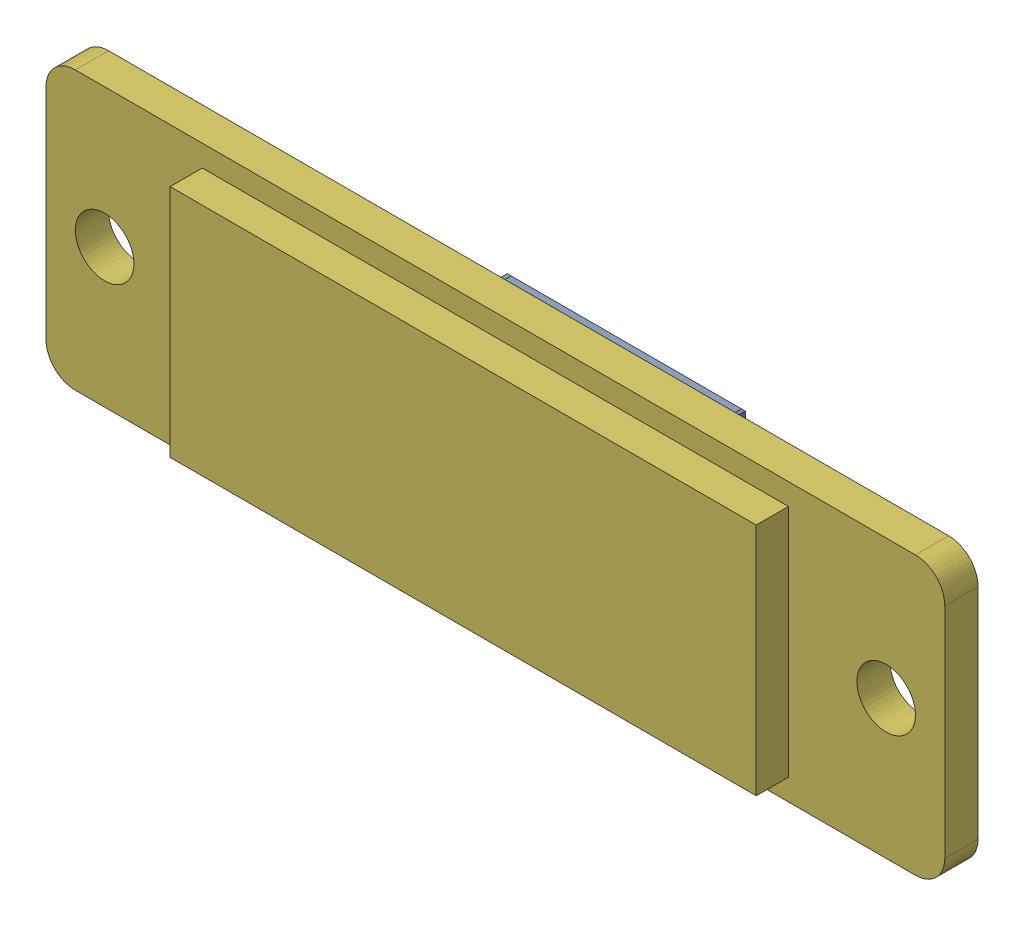
SolidWorks assembly OLED-JT, configuration Default. Lengths in mm.
Overall size (46 14.2 8.35).
36 component instances, 8 part files, 0 mates.
Components (placement in the parent):
- 4PIN-1: 4PIN [Default] at (6.97 53 -1.7) x (0 -1 0) z (0 0 -1) size (8.63 12.19 5)
  - 739168144-1: 739168144 [Default] at (53.0673 7.4627 4.5) size (6.13 11.96 0.5)
    - Extruded (28)_1-1: Extruded (28)_1 [Default] at origin size (6.13 11.96 0.5)
  - 739168272-1: 739168272 [Default] at (56.0287 7.45 0) size (0.2 12 4.5)
    - Extruded (29)_1-1: Extruded (29)_1 [Default] at origin size (0.2 12 4.5)
  - 739168528-1: 739168528 [Default] at (53.738 13.4444 0) size (7.47 0.2 5)
    - Extruded (30)_1-1: Extruded (30)_1 [Default] at origin size (7.47 0.2 5)
  - 739168656-1: 739168656 [Default] at (53.066 7.4627 0) size (6.12 11.96 0.5)
    - Extruded (31)_1-1: Extruded (31)_1 [Default] at origin size (6.12 11.96 0.5)
  - 739168528_1-1: 739168528_1 [Default] at (53.738 1.4556 0) size (7.47 0.2 5)
    - Extruded (30)_1-1: Extruded (30)_1 [Default] at origin size (7.47 0.2 5)
  - 654176208-1: 654176208 [Default] at (56.1305 4.4303 2.5) x (0 0 -1) z (-1 0 0) size (0.8 0.8 5)
    - Cylinder (1)_1-1: Cylinder (1)_1 [Default] at origin size (0.8 0.8 5)
  - 654176208_1-1: 654176208_1 [Default] at (56.1305 6.4661 2.5) x (0 0 -1) z (-1 0 0) size (0.8 0.8 5)
    - Cylinder (1)_1-1: Cylinder (1)_1 [Default] at origin size (0.8 0.8 5)
  - 654176208_2-1: 654176208_2 [Default] at (56.1305 8.4727 2.5) x (0 0 -1) z (-1 0 0) size (0.8 0.8 5)
    - Cylinder (1)_1-1: Cylinder (1)_1 [Default] at origin size (0.8 0.8 5)
  - 654176208_3-1: 654176208_3 [Default] at (56.1305 10.4501 2.5) x (0 0 -1) z (-1 0 0) size (0.8 0.8 5)
    - Cylinder (1)_1-1: Cylinder (1)_1 [Default] at origin size (0.8 0.8 5)
  - 654176328-1: 654176328 [Default] at (56.1065 4.4273 0) x (0 1 0) z (0 0 1) size (0.8 0.8 2.5)
    - Cylinder (2)_1-1: Cylinder (2)_1 [Default] at origin size (0.8 0.8 2.5)
  - 654176328_1-1: 654176328_1 [Default] at (56.1319 6.4593 0) x (0 1 0) z (0 0 1) size (0.8 0.8 2.5)
    - Cylinder (2)_1-1: Cylinder (2)_1 [Default] at origin size (0.8 0.8 2.5)
  - 654176328_2-1: 654176328_2 [Default] at (56.1573 8.4659 0) x (0 1 0) z (0 0 1) size (0.8 0.8 2.5)
    - Cylinder (2)_1-1: Cylinder (2)_1 [Default] at origin size (0.8 0.8 2.5)
  - 654176328_3-1: 654176328_3 [Default] at (56.1319 10.4471 0) x (0 1 0) z (0 0 1) size (0.8 0.8 2.5)
    - Cylinder (2)_1-1: Cylinder (2)_1 [Default] at origin size (0.8 0.8 2.5)
  - 654176448-1: 654176448 [Default] at (58.6119 4.4302 0.4) x (0 0 -1) z (-1 0 0) size (0.8 0.8 2.5)
    - Cylinder (3)_1-1: Cylinder (3)_1 [Default] at origin size (0.8 0.8 2.5)
  - 654176448_1-1: 654176448_1 [Default] at (58.6372 6.4622 0.4) x (0 0 -1) z (-1 0 0) size (0.8 0.8 2.5)
    - Cylinder (3)_1-1: Cylinder (3)_1 [Default] at origin size (0.8 0.8 2.5)
  - 654176448_2-1: 654176448_2 [Default] at (58.6372 8.4688 0.4) x (0 0 -1) z (-1 0 0) size (0.8 0.8 2.5)
    - Cylinder (3)_1-1: Cylinder (3)_1 [Default] at origin size (0.8 0.8 2.5)
  - 654176448_3-1: 654176448_3 [Default] at (58.6372 10.45 0.4) x (0 0 -1) z (-1 0 0) size (0.8 0.8 2.5)
    - Cylinder (3)_1-1: Cylinder (3)_1 [Default] at origin size (0.8 0.8 2.5)
- OLED-JT-0-1: OLED-JT-0 [Default] at origin size (46 14.2 3.35)
